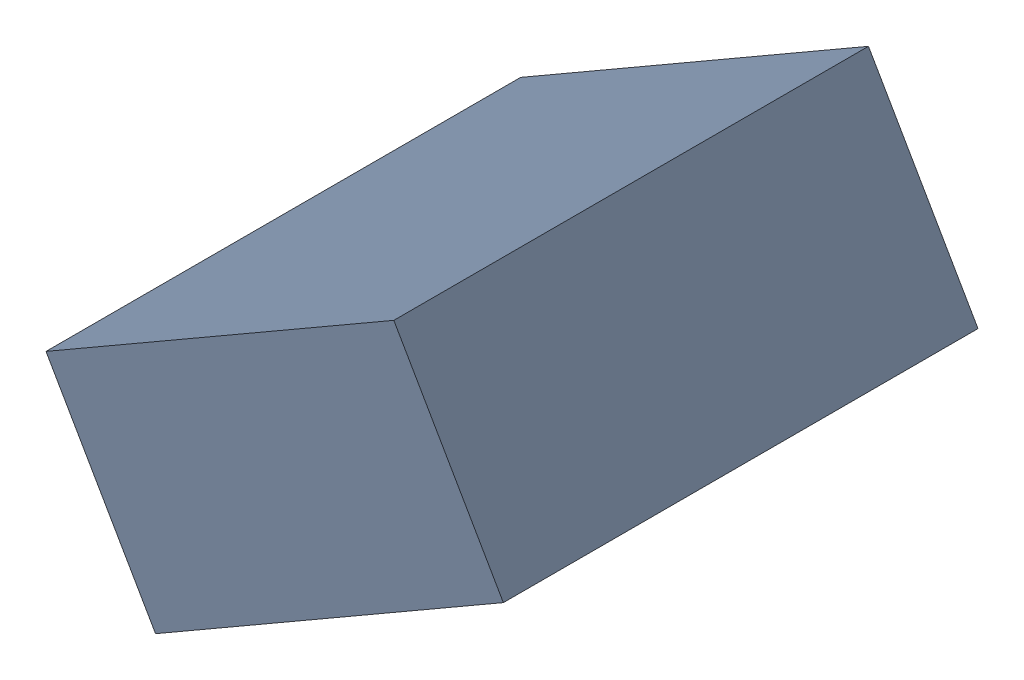
SolidWorks assembly C27_TDA5, configuration Standard. Lengths in mm.
Overall size (1.25 1.07 1.3).
2 component instances, 1 part files, 0 mates.
Components (placement in the parent):
- 885542920-1: 885542920 [Standard] at (-49.2641 -29.6478 0) size (1.25 1.07 1.3)
  - Extruded_24-1: Extruded_24 [Standard] at origin size (1.25 1.07 1.3)
